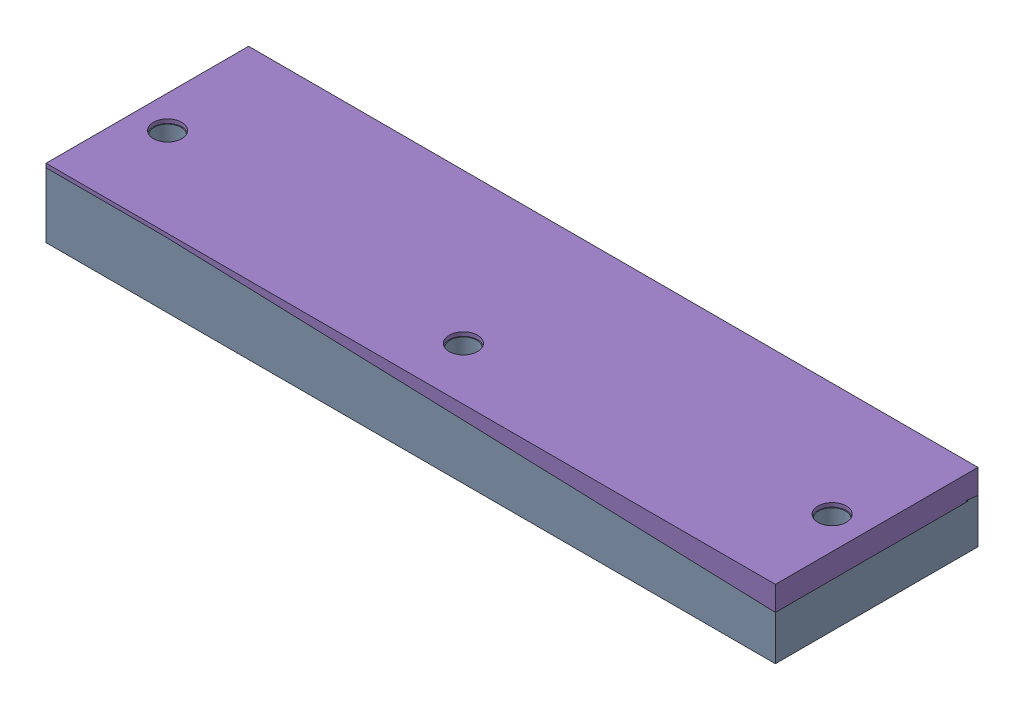
SolidWorks assembly Assemblage_Moule_Patins, configuration Défaut. Lengths in mm.
Overall size (90 8.49 25).
5 component instances, 5 part files, 8 mates.
Components (placement in the parent):
- Moule_Patins-1: Moule_Patins [Défaut] at origin size (90 8 25)
- Patin_Pince-1: Patin_Pince [Défaut] at (0 8 -6) size (80 3.5 8)
- Patin_Pince_Moyen-1: Patin_Pince_Moyen [Défaut] at (-37 8 6) x (0 0 -1) z (1 0 0) size (8 3.5 32)
- Patin_Pince_Petit-1: Patin_Pince_Petit [Défaut] at (24 8 6) x (0 0 1) z (-1 0 0) size (8 3.5 19)
- Toit_Moule_Patins-1: Toit_Moule_Patins [Défaut] at (0 5.4851 0) size (90 3 25)
Mates (geometry in assembly coordinates):
- Coïncidente1: coincident: point of assembly; point of Moule_Patins-1; point of Patin_Pince-1
- Coïncidente2: coincident: point of assembly; point of Moule_Patins-1; point of Patin_Pince-1
- Coïncidente3: coincident: point of assembly; point of Moule_Patins-1; point of Patin_Pince_Petit-1
- Coïncidente4: coincident: point of assembly; point of Moule_Patins-1; point of Patin_Pince_Petit-1
- Coïncidente5: coincident: point of assembly; point of Moule_Patins-1; point of Patin_Pince_Moyen-1
- Coïncidente6: coincident: point of assembly; point of Moule_Patins-1; point of Patin_Pince_Moyen-1
- Coïncidente7: coincident: plane of Moule_Patins-1 through (-45 8 12.5) normal (-1 0 0); plane of Toit_Moule_Patins-1 through (-45 8.4851 -12.5) normal (-1 0 0)
- Coïncidente8: coincident aligned: plane of Moule_Patins-1 through (-45 8 12.5) normal (0 0 1); plane of Toit_Moule_Patins-1 through (-45 8.4851 12.5) normal (0 0 1)
